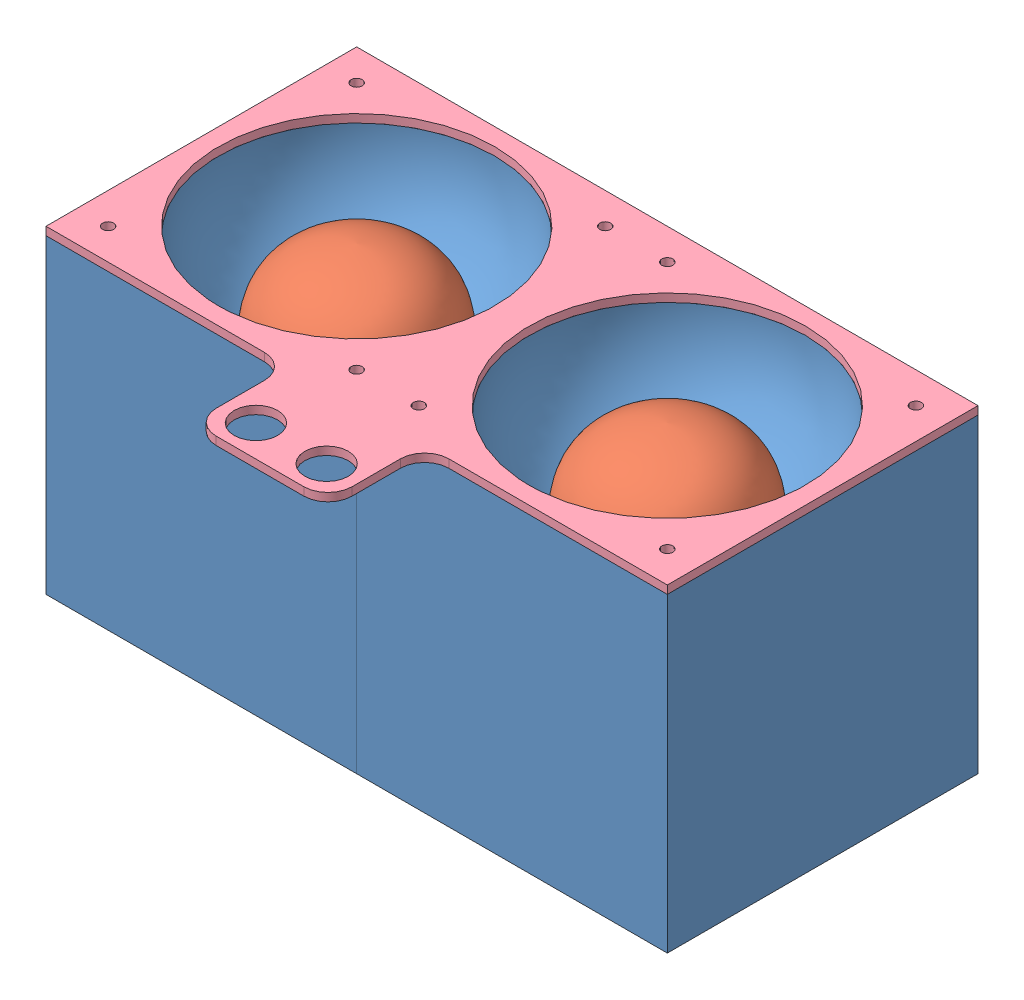
SolidWorks assembly backup-light-sensor, configuration Default. Lengths in mm.
Overall size (232.38 152.86 153.64).
7 component instances, 4 part files, 14 mates.
Components (placement in the parent):
- mount-1: mount [Default] at (-29.2723 1.8668 164.9511) size (114.3 114.3 114.3)
- bulb-1: bulb [Default] at (27.8777 22.1868 107.8011) x (0.546342 0 -0.837562) z (0 -1 0) size (88.06 88.06 116.84)
- socket-1: socket [Default] at (27.8777 -3.2132 107.8011) x (0.990876 0 0.134779) z (-0.134779 0 0.990876) size (41.91 55.88 41.91)
- faceplate-1: faceplate [Default] at (-29.2723 116.1668 164.9511) size (228.6 3 149.86)
- mount-2: mount [Default] at (85.0277 1.8668 164.9511) size (114.3 114.3 114.3)
- socket-2: socket [Default] at (142.1777 -3.2132 107.8011) size (41.91 55.88 41.91)
- bulb-2: bulb [Default] at (142.1777 22.1868 107.8011) x (1 0 0) z (0 -1 0) size (88.06 88.06 116.84)
Mates (geometry in assembly coordinates):
- Concentric1: concentric anti-aligned: cylinder of test mount-1 through (27.8777 1.8668 107.8011) axis (0 1 0) radius 19.3675; cylinder of socket-1 through (27.8777 8.2168 107.8011) axis (0 -1 0) radius 19.3675
- Coincident1: coincident anti-aligned: plane of test mount-1 through (27.8777 8.2168 107.8011) normal (0 1 0); plane of socket-1 through (27.8777 8.2168 107.8011) normal (0 -1 0)
- Concentric2: concentric aligned: cylinder of bulb-1 through (27.8777 -3.2132 107.8011) axis (0 1 0) radius 12.7; cylinder of socket-1 through (27.8777 -3.2132 107.8011) axis (0 1 0) radius 13.97
- Coincident2: coincident anti-aligned: plane of bulb-1 through (27.8777 -3.2132 107.8011) normal (0 -1 0); plane of socket-1 through (27.8777 -3.2132 107.8011) normal (0 1 0)
- Coincident3: coincident aligned: plane of test mount-1 through (-29.2723 116.1668 50.6511) normal (0 0 -1); plane of light mount faceplate double with sensor mount-1 through (-29.2723 119.1668 50.6511) normal (0 0 -1)
- Coincident4: coincident aligned: plane of test mount-1 through (-29.2723 116.1668 164.9511) normal (-1 0 0); plane of light mount faceplate double with sensor mount-1 through (-29.2723 119.1668 164.9511) normal (-1 0 0)
- Coincident5: coincident anti-aligned: plane of test mount-1 through (-29.2723 116.1668 164.9511) normal (0 1 0); plane of light mount faceplate double with sensor mount-1 through (-29.2723 116.1668 164.9511) normal (0 -1 0)
- Coincident6: coincident aligned: plane of test mount-1 through (-29.2723 116.1668 50.6511) normal (0 0 -1); plane of test mount-2 through (85.0277 116.1668 50.6511) normal (0 0 -1)
- Coincident7: coincident anti-aligned: plane of test mount-1 through (85.0277 116.1668 164.9511) normal (1 0 0); plane of test mount-2 through (85.0277 116.1668 164.9511) normal (-1 0 0)
- Coincident8: coincident aligned: circle of light mount faceplate double with sensor mount-1; plane of test mount-2 through (85.0277 116.1668 164.9511) normal (0 1 0)
- Concentric3: concentric anti-aligned: cylinder of test mount-2 through (142.1777 8.2168 107.8011) axis (0 1 0) radius 28.575; cylinder of socket-2 through (142.1777 8.2168 107.8011) axis (0 -1 0) radius 19.3675
- Coincident9: coincident anti-aligned: plane of test mount-2 through (142.1777 8.2168 107.8011) normal (0 1 0); plane of socket-2 through (142.1777 8.2168 107.8011) normal (0 -1 0)
- Coincident10: coincident anti-aligned: plane of socket-2 through (142.1777 -3.2132 107.8011) normal (0 1 0); plane of bulb-2 through (142.1777 -3.2132 107.8011) normal (0 -1 0)
- Concentric4: concentric aligned: cylinder of socket-2 through (142.1777 -3.2132 107.8011) axis (0 1 0) radius 13.97; cylinder of bulb-2 through (142.1777 -3.2132 107.8011) axis (0 1 0) radius 12.7
